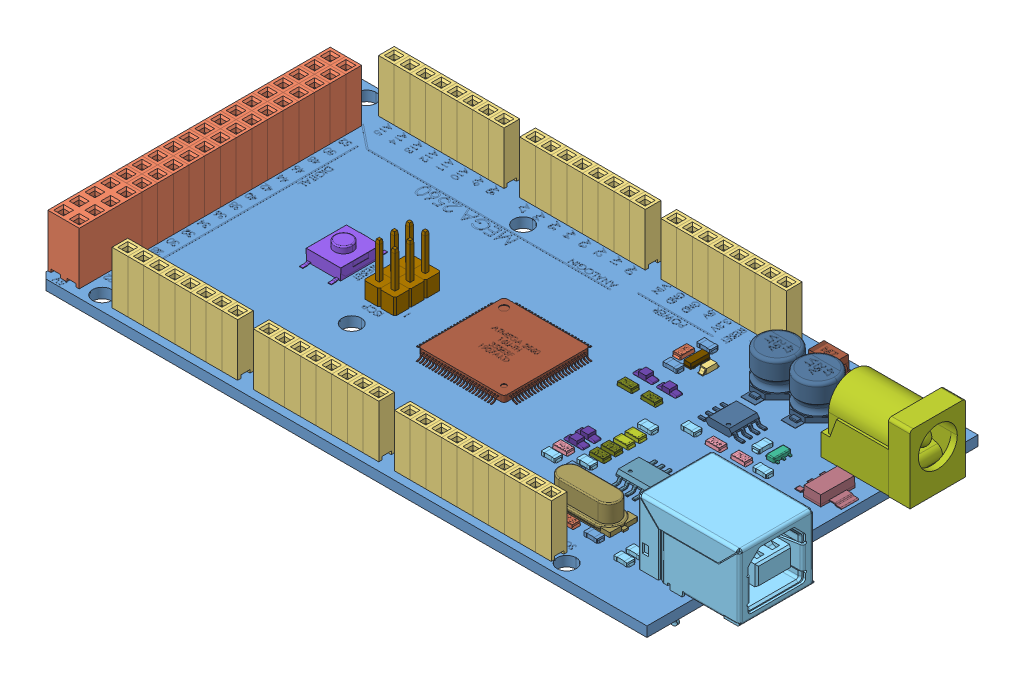
SolidWorks assembly Arduino Mega ATmega 2560, configuration Default. Lengths in mm.
Overall size (109.91 15.26 53.6).
200 component instances, 29 part files, 0 mates.
Components (placement in the parent):
- Arduino Mega ATmega 2560.STEP-1: Arduino Mega ATmega 2560.STEP [Default] at origin size (109.91 15.26 53.6)
  - Arduino Mega PCB.STEP-1: Arduino Mega PCB.STEP [Default] at origin size (101.8 1.64 53.6)
  - headerFemalex18x2.STEP-1: headerFemalex18x2.STEP [Default] at (-44.415 1.63 17.88) x (0 0 -1) z (1 0 0) size (45.72 11.5 5.08)
  - headerFemale.STEP-1: headerFemale.STEP [Default] at (-30.205 1.63 24.23) size (2.54 11.5 2.54)
  - headerFemale.STEP-2: headerFemale.STEP [Default] at (-27.665 1.63 24.23) size (2.54 11.5 2.54)
  - headerFemale.STEP-3: headerFemale.STEP [Default] at (-25.125 1.63 24.23) size (2.54 11.5 2.54)
  - headerFemale.STEP-4: headerFemale.STEP [Default] at (-22.585 1.63 24.23) size (2.54 11.5 2.54)
  - headerFemale.STEP-5: headerFemale.STEP [Default] at (-20.045 1.63 24.23) size (2.54 11.5 2.54)
  - headerFemale.STEP-6: headerFemale.STEP [Default] at (-17.505 1.63 24.23) size (2.54 11.5 2.54)
  - headerFemale.STEP-7: headerFemale.STEP [Default] at (-14.965 1.63 24.23) size (2.54 11.5 2.54)
  - headerFemale.STEP-8: headerFemale.STEP [Default] at (-12.425 1.63 24.23) size (2.54 11.5 2.54)
  - headerFemale.STEP-9: headerFemale.STEP [Default] at (-7.345 1.63 24.23) size (2.54 11.5 2.54)
  - headerFemale.STEP-10: headerFemale.STEP [Default] at (-4.805 1.63 24.23) size (2.54 11.5 2.54)
  - headerFemale.STEP-11: headerFemale.STEP [Default] at (-2.265 1.63 24.23) size (2.54 11.5 2.54)
  - headerFemale.STEP-12: headerFemale.STEP [Default] at (0.275 1.63 24.23) size (2.54 11.5 2.54)
  - headerFemale.STEP-13: headerFemale.STEP [Default] at (2.815 1.63 24.23) size (2.54 11.5 2.54)
  - headerFemale.STEP-14: headerFemale.STEP [Default] at (5.355 1.63 24.23) size (2.54 11.5 2.54)
  - headerFemale.STEP-15: headerFemale.STEP [Default] at (7.895 1.63 24.23) size (2.54 11.5 2.54)
  - headerFemale.STEP-16: headerFemale.STEP [Default] at (10.435 1.63 24.23) size (2.54 11.5 2.54)
  - headerFemale.STEP-17: headerFemale.STEP [Default] at (15.515 1.63 24.23) size (2.54 11.5 2.54)
  - headerFemale.STEP-18: headerFemale.STEP [Default] at (18.055 1.63 24.23) size (2.54 11.5 2.54)
  - headerFemale.STEP-19: headerFemale.STEP [Default] at (20.595 1.63 24.23) size (2.54 11.5 2.54)
  - headerFemale.STEP-20: headerFemale.STEP [Default] at (23.135 1.63 24.23) size (2.54 11.5 2.54)
  - headerFemale.STEP-21: headerFemale.STEP [Default] at (25.675 1.63 24.23) size (2.54 11.5 2.54)
  - headerFemale.STEP-22: headerFemale.STEP [Default] at (28.215 1.63 24.23) size (2.54 11.5 2.54)
  - headerFemale.STEP-23: headerFemale.STEP [Default] at (30.755 1.63 24.23) size (2.54 11.5 2.54)
  - headerFemale.STEP-24: headerFemale.STEP [Default] at (33.295 1.63 24.23) size (2.54 11.5 2.54)
  - headerFemale.STEP-25: headerFemale.STEP [Default] at (35.835 1.63 24.23) size (2.54 11.5 2.54)
  - headerFemale.STEP-26: headerFemale.STEP [Default] at (38.375 1.63 24.23) size (2.54 11.5 2.54)
  - headerFemale.STEP-27: headerFemale.STEP [Default] at (-35.525 1.63 -24.23) size (2.54 11.5 2.54)
  - headerFemale.STEP-28: headerFemale.STEP [Default] at (-32.985 1.63 -24.23) size (2.54 11.5 2.54)
  - headerFemale.STEP-29: headerFemale.STEP [Default] at (-30.445 1.63 -24.23) size (2.54 11.5 2.54)
  - headerFemale.STEP-30: headerFemale.STEP [Default] at (-27.905 1.63 -24.23) size (2.54 11.5 2.54)
  - headerFemale.STEP-31: headerFemale.STEP [Default] at (-25.365 1.63 -24.23) size (2.54 11.5 2.54)
  - headerFemale.STEP-32: headerFemale.STEP [Default] at (-22.825 1.63 -24.23) size (2.54 11.5 2.54)
  - headerFemale.STEP-33: headerFemale.STEP [Default] at (-20.285 1.63 -24.23) size (2.54 11.5 2.54)
  - headerFemale.STEP-34: headerFemale.STEP [Default] at (-17.745 1.63 -24.23) size (2.54 11.5 2.54)
  - headerFemale.STEP-35: headerFemale.STEP [Default] at (-12.665 1.63 -24.23) size (2.54 11.5 2.54)
  - headerFemale.STEP-36: headerFemale.STEP [Default] at (-10.125 1.63 -24.23) size (2.54 11.5 2.54)
  - headerFemale.STEP-37: headerFemale.STEP [Default] at (-7.585 1.63 -24.23) size (2.54 11.5 2.54)
  - headerFemale.STEP-38: headerFemale.STEP [Default] at (-5.045 1.63 -24.23) size (2.54 11.5 2.54)
  - headerFemale.STEP-39: headerFemale.STEP [Default] at (-2.505 1.63 -24.23) size (2.54 11.5 2.54)
  - headerFemale.STEP-40: headerFemale.STEP [Default] at (0.035 1.63 -24.23) size (2.54 11.5 2.54)
  - headerFemale.STEP-41: headerFemale.STEP [Default] at (2.575 1.63 -24.23) size (2.54 11.5 2.54)
  - headerFemale.STEP-42: headerFemale.STEP [Default] at (5.115 1.63 -24.23) size (2.54 11.5 2.54)
  - headerFemale.STEP-43: headerFemale.STEP [Default] at (10.195 1.63 -24.23) size (2.54 11.5 2.54)
  - headerFemale.STEP-44: headerFemale.STEP [Default] at (12.735 1.63 -24.23) size (2.54 11.5 2.54)
  - headerFemale.STEP-45: headerFemale.STEP [Default] at (15.275 1.63 -24.23) size (2.54 11.5 2.54)
  - headerFemale.STEP-46: headerFemale.STEP [Default] at (17.815 1.63 -24.23) size (2.54 11.5 2.54)
  - headerFemale.STEP-47: headerFemale.STEP [Default] at (20.355 1.63 -24.23) size (2.54 11.5 2.54)
  - headerFemale.STEP-48: headerFemale.STEP [Default] at (22.895 1.63 -24.23) size (2.54 11.5 2.54)
  - headerFemale.STEP-49: headerFemale.STEP [Default] at (25.435 1.63 -24.23) size (2.54 11.5 2.54)
  - headerFemale.STEP-50: headerFemale.STEP [Default] at (27.975 1.63 -24.23) size (2.54 11.5 2.54)
  - solder.STEP-1: solder.STEP [Default] at (-46.9277 0 24.2186) x (-0.837169 0 -0.546944) z (-0.546944 0 0.837169) size (1.17 0.65 1.17)
  - solder.STEP-2: solder.STEP [Default] at (-44.3877 0 24.2186) x (-0.837169 0 -0.546944) z (-0.546944 0 0.837169) size (1.17 0.65 1.17)
  - solder.STEP-3: solder.STEP [Default] at (-46.9277 0 21.6786) x (-0.837169 0 -0.546944) z (-0.546944 0 0.837169) size (1.17 0.65 1.17)
  - solder.STEP-4: solder.STEP [Default] at (-44.3877 0 21.6786) x (-0.837169 0 -0.546944) z (-0.546944 0 0.837169) size (1.17 0.65 1.17)
  - solder.STEP-5: solder.STEP [Default] at (-46.9277 0 19.1386) x (-0.837169 0 -0.546944) z (-0.546944 0 0.837169) size (1.17 0.65 1.17)
  - solder.STEP-6: solder.STEP [Default] at (-44.3877 0 19.1386) x (-0.837169 0 -0.546944) z (-0.546944 0 0.837169) size (1.17 0.65 1.17)
  - solder.STEP-7: solder.STEP [Default] at (-46.9277 0 16.5986) x (-0.837169 0 -0.546944) z (-0.546944 0 0.837169) size (1.17 0.65 1.17)
  - solder.STEP-8: solder.STEP [Default] at (-44.3877 0 16.5986) x (-0.837169 0 -0.546944) z (-0.546944 0 0.837169) size (1.17 0.65 1.17)
  - solder.STEP-9: solder.STEP [Default] at (-46.9277 0 14.0586) x (-0.837169 0 -0.546944) z (-0.546944 0 0.837169) size (1.17 0.65 1.17)
  - solder.STEP-10: solder.STEP [Default] at (-44.3877 0 14.0586) x (-0.837169 0 -0.546944) z (-0.546944 0 0.837169) size (1.17 0.65 1.17)
  - solder.STEP-11: solder.STEP [Default] at (-46.9277 0 11.5186) x (-0.837169 0 -0.546944) z (-0.546944 0 0.837169) size (1.17 0.65 1.17)
  - solder.STEP-12: solder.STEP [Default] at (-44.3877 0 11.5186) x (-0.837169 0 -0.546944) z (-0.546944 0 0.837169) size (1.17 0.65 1.17)
  - solder.STEP-13: solder.STEP [Default] at (-46.9277 0 8.9786) x (-0.837169 0 -0.546944) z (-0.546944 0 0.837169) size (1.17 0.65 1.17)
  - solder.STEP-14: solder.STEP [Default] at (-44.3877 0 8.9786) x (-0.837169 0 -0.546944) z (-0.546944 0 0.837169) size (1.17 0.65 1.17)
  - solder.STEP-15: solder.STEP [Default] at (-46.9277 0 6.4386) x (-0.837169 0 -0.546944) z (-0.546944 0 0.837169) size (1.17 0.65 1.17)
  - solder.STEP-16: solder.STEP [Default] at (-44.3877 0 6.4386) x (-0.837169 0 -0.546944) z (-0.546944 0 0.837169) size (1.17 0.65 1.17)
  - solder.STEP-17: solder.STEP [Default] at (-46.9277 0 3.8986) x (-0.837169 0 -0.546944) z (-0.546944 0 0.837169) size (1.17 0.65 1.17)
  - solder.STEP-18: solder.STEP [Default] at (-44.3877 0 3.8986) x (-0.837169 0 -0.546944) z (-0.546944 0 0.837169) size (1.17 0.65 1.17)
  - solder.STEP-19: solder.STEP [Default] at (-46.9277 0 1.3586) x (-0.837169 0 -0.546944) z (-0.546944 0 0.837169) size (1.17 0.65 1.17)
  - solder.STEP-20: solder.STEP [Default] at (-44.3877 0 1.3586) x (-0.837169 0 -0.546944) z (-0.546944 0 0.837169) size (1.17 0.65 1.17)
  - solder.STEP-21: solder.STEP [Default] at (-46.9277 0 -1.1814) x (-0.837169 0 -0.546944) z (-0.546944 0 0.837169) size (1.17 0.65 1.17)
  - solder.STEP-22: solder.STEP [Default] at (-44.3877 0 -1.1814) x (-0.837169 0 -0.546944) z (-0.546944 0 0.837169) size (1.17 0.65 1.17)
  - solder.STEP-23: solder.STEP [Default] at (-46.9277 0 -3.7214) x (-0.837169 0 -0.546944) z (-0.546944 0 0.837169) size (1.17 0.65 1.17)
  - solder.STEP-24: solder.STEP [Default] at (-44.3877 0 -3.7214) x (-0.837169 0 -0.546944) z (-0.546944 0 0.837169) size (1.17 0.65 1.17)
  - solder.STEP-25: solder.STEP [Default] at (-46.9277 0 -6.2614) x (-0.837169 0 -0.546944) z (-0.546944 0 0.837169) size (1.17 0.65 1.17)
  - solder.STEP-26: solder.STEP [Default] at (-44.3877 0 -6.2614) x (-0.837169 0 -0.546944) z (-0.546944 0 0.837169) size (1.17 0.65 1.17)
  - solder.STEP-27: solder.STEP [Default] at (-46.9277 0 -8.8014) x (-0.837169 0 -0.546944) z (-0.546944 0 0.837169) size (1.17 0.65 1.17)
  - solder.STEP-28: solder.STEP [Default] at (-44.3877 0 -8.8014) x (-0.837169 0 -0.546944) z (-0.546944 0 0.837169) size (1.17 0.65 1.17)
  - solder.STEP-29: solder.STEP [Default] at (-46.9277 0 -11.3414) x (-0.837169 0 -0.546944) z (-0.546944 0 0.837169) size (1.17 0.65 1.17)
  - solder.STEP-30: solder.STEP [Default] at (-44.3877 0 -11.3414) x (-0.837169 0 -0.546944) z (-0.546944 0 0.837169) size (1.17 0.65 1.17)
  - solder.STEP-31: solder.STEP [Default] at (-46.9277 0 -13.8814) x (-0.837169 0 -0.546944) z (-0.546944 0 0.837169) size (1.17 0.65 1.17)
  - solder.STEP-32: solder.STEP [Default] at (-44.3877 0 -13.8814) x (-0.837169 0 -0.546944) z (-0.546944 0 0.837169) size (1.17 0.65 1.17)
  - solder.STEP-33: solder.STEP [Default] at (-46.9277 0 -16.4214) x (-0.837169 0 -0.546944) z (-0.546944 0 0.837169) size (1.17 0.65 1.17)
  - solder.STEP-34: solder.STEP [Default] at (-44.3877 0 -16.4214) x (-0.837169 0 -0.546944) z (-0.546944 0 0.837169) size (1.17 0.65 1.17)
  - solder.STEP-35: solder.STEP [Default] at (-46.9277 0 -18.9614) x (-0.837169 0 -0.546944) z (-0.546944 0 0.837169) size (1.17 0.65 1.17)
  - solder.STEP-36: solder.STEP [Default] at (-44.3877 0 -18.9614) x (-0.837169 0 -0.546944) z (-0.546944 0 0.837169) size (1.17 0.65 1.17)
  - solder.STEP-37: solder.STEP [Default] at (-36.5404 0 24.2186) x (-0.837169 0 -0.546944) z (-0.546944 0 0.837169) size (1.17 0.65 1.17)
  - solder.STEP-38: solder.STEP [Default] at (-34.0004 0 24.2186) x (-0.837169 0 -0.546944) z (-0.546944 0 0.837169) size (1.17 0.65 1.17)
  - solder.STEP-39: solder.STEP [Default] at (-31.4604 0 24.2186) x (-0.837169 0 -0.546944) z (-0.546944 0 0.837169) size (1.17 0.65 1.17)
  - solder.STEP-40: solder.STEP [Default] at (-28.9204 0 24.2186) x (-0.837169 0 -0.546944) z (-0.546944 0 0.837169) size (1.17 0.65 1.17)
  - solder.STEP-41: solder.STEP [Default] at (-26.3804 0 24.2186) x (-0.837169 0 -0.546944) z (-0.546944 0 0.837169) size (1.17 0.65 1.17)
  - solder.STEP-42: solder.STEP [Default] at (-23.8404 0 24.2186) x (-0.837169 0 -0.546944) z (-0.546944 0 0.837169) size (1.17 0.65 1.17)
  - solder.STEP-43: solder.STEP [Default] at (-21.3004 0 24.2186) x (-0.837169 0 -0.546944) z (-0.546944 0 0.837169) size (1.17 0.65 1.17)
  - solder.STEP-44: solder.STEP [Default] at (-18.7604 0 24.2186) x (-0.837169 0 -0.546944) z (-0.546944 0 0.837169) size (1.17 0.65 1.17)
  - solder.STEP-45: solder.STEP [Default] at (-13.6804 0 24.2186) x (-0.837169 0 -0.546944) z (-0.546944 0 0.837169) size (1.17 0.65 1.17)
  - solder.STEP-46: solder.STEP [Default] at (-11.1404 0 24.2186) x (-0.837169 0 -0.546944) z (-0.546944 0 0.837169) size (1.17 0.65 1.17)
  - solder.STEP-47: solder.STEP [Default] at (-8.6004 0 24.2186) x (-0.837169 0 -0.546944) z (-0.546944 0 0.837169) size (1.17 0.65 1.17)
  - solder.STEP-48: solder.STEP [Default] at (-6.0604 0 24.2186) x (-0.837169 0 -0.546944) z (-0.546944 0 0.837169) size (1.17 0.65 1.17)
  - solder.STEP-49: solder.STEP [Default] at (-3.5204 0 24.2186) x (-0.837169 0 -0.546944) z (-0.546944 0 0.837169) size (1.17 0.65 1.17)
  - solder.STEP-50: solder.STEP [Default] at (-0.9804 0 24.2186) x (-0.837169 0 -0.546944) z (-0.546944 0 0.837169) size (1.17 0.65 1.17)
  - solder.STEP-51: solder.STEP [Default] at (1.5596 0 24.2186) x (-0.837169 0 -0.546944) z (-0.546944 0 0.837169) size (1.17 0.65 1.17)
  - solder.STEP-52: solder.STEP [Default] at (4.0996 0 24.2186) x (-0.837169 0 -0.546944) z (-0.546944 0 0.837169) size (1.17 0.65 1.17)
  - solder.STEP-53: solder.STEP [Default] at (9.1796 0 24.2186) x (-0.837169 0 -0.546944) z (-0.546944 0 0.837169) size (1.17 0.65 1.17)
  - solder.STEP-54: solder.STEP [Default] at (11.7196 0 24.2186) x (-0.837169 0 -0.546944) z (-0.546944 0 0.837169) size (1.17 0.65 1.17)
  - solder.STEP-55: solder.STEP [Default] at (14.2596 0 24.2186) x (-0.837169 0 -0.546944) z (-0.546944 0 0.837169) size (1.17 0.65 1.17)
  - solder.STEP-56: solder.STEP [Default] at (16.7996 0 24.2186) x (-0.837169 0 -0.546944) z (-0.546944 0 0.837169) size (1.17 0.65 1.17)
  - solder.STEP-57: solder.STEP [Default] at (19.3396 0 24.2186) x (-0.837169 0 -0.546944) z (-0.546944 0 0.837169) size (1.17 0.65 1.17)
  - solder.STEP-58: solder.STEP [Default] at (21.8796 0 24.2186) x (-0.837169 0 -0.546944) z (-0.546944 0 0.837169) size (1.17 0.65 1.17)
  - solder.STEP-59: solder.STEP [Default] at (24.4196 0 24.2186) x (-0.837169 0 -0.546944) z (-0.546944 0 0.837169) size (1.17 0.65 1.17)
  - solder.STEP-60: solder.STEP [Default] at (26.9596 0 24.2186) x (-0.837169 0 -0.546944) z (-0.546944 0 0.837169) size (1.17 0.65 1.17)
  - solder.STEP-61: solder.STEP [Default] at (29.4996 0 24.2186) x (-0.837169 0 -0.546944) z (-0.546944 0 0.837169) size (1.17 0.65 1.17)
  - solder.STEP-62: solder.STEP [Default] at (32.0396 0 24.2186) x (-0.837169 0 -0.546944) z (-0.546944 0 0.837169) size (1.17 0.65 1.17)
  - solder.STEP-63: solder.STEP [Default] at (-41.8709 0 -24.251) x (-0.837169 0 -0.546944) z (-0.546944 0 0.837169) size (1.17 0.65 1.17)
  - solder.STEP-64: solder.STEP [Default] at (-39.3309 0 -24.251) x (-0.837169 0 -0.546944) z (-0.546944 0 0.837169) size (1.17 0.65 1.17)
  - solder.STEP-65: solder.STEP [Default] at (-36.7909 0 -24.251) x (-0.837169 0 -0.546944) z (-0.546944 0 0.837169) size (1.17 0.65 1.17)
  - solder.STEP-66: solder.STEP [Default] at (-34.2509 0 -24.251) x (-0.837169 0 -0.546944) z (-0.546944 0 0.837169) size (1.17 0.65 1.17)
  - solder.STEP-67: solder.STEP [Default] at (-31.7109 0 -24.251) x (-0.837169 0 -0.546944) z (-0.546944 0 0.837169) size (1.17 0.65 1.17)
  - solder.STEP-68: solder.STEP [Default] at (-29.1709 0 -24.251) x (-0.837169 0 -0.546944) z (-0.546944 0 0.837169) size (1.17 0.65 1.17)
  - solder.STEP-69: solder.STEP [Default] at (-26.6309 0 -24.251) x (-0.837169 0 -0.546944) z (-0.546944 0 0.837169) size (1.17 0.65 1.17)
  - solder.STEP-70: solder.STEP [Default] at (-24.0909 0 -24.251) x (-0.837169 0 -0.546944) z (-0.546944 0 0.837169) size (1.17 0.65 1.17)
  - solder.STEP-71: solder.STEP [Default] at (-19.0109 0 -24.251) x (-0.837169 0 -0.546944) z (-0.546944 0 0.837169) size (1.17 0.65 1.17)
  - solder.STEP-72: solder.STEP [Default] at (-16.4709 0 -24.251) x (-0.837169 0 -0.546944) z (-0.546944 0 0.837169) size (1.17 0.65 1.17)
  - solder.STEP-73: solder.STEP [Default] at (-13.9309 0 -24.251) x (-0.837169 0 -0.546944) z (-0.546944 0 0.837169) size (1.17 0.65 1.17)
  - solder.STEP-74: solder.STEP [Default] at (-11.3909 0 -24.251) x (-0.837169 0 -0.546944) z (-0.546944 0 0.837169) size (1.17 0.65 1.17)
  - solder.STEP-75: solder.STEP [Default] at (-8.8509 0 -24.251) x (-0.837169 0 -0.546944) z (-0.546944 0 0.837169) size (1.17 0.65 1.17)
  - solder.STEP-76: solder.STEP [Default] at (-6.3109 0 -24.251) x (-0.837169 0 -0.546944) z (-0.546944 0 0.837169) size (1.17 0.65 1.17)
  - solder.STEP-77: solder.STEP [Default] at (-3.7709 0 -24.251) x (-0.837169 0 -0.546944) z (-0.546944 0 0.837169) size (1.17 0.65 1.17)
  - solder.STEP-78: solder.STEP [Default] at (-1.2309 0 -24.251) x (-0.837169 0 -0.546944) z (-0.546944 0 0.837169) size (1.17 0.65 1.17)
  - solder.STEP-79: solder.STEP [Default] at (3.8491 0 -24.251) x (-0.837169 0 -0.546944) z (-0.546944 0 0.837169) size (1.17 0.65 1.17)
  - solder.STEP-80: solder.STEP [Default] at (6.3891 0 -24.251) x (-0.837169 0 -0.546944) z (-0.546944 0 0.837169) size (1.17 0.65 1.17)
  - solder.STEP-81: solder.STEP [Default] at (8.9291 0 -24.251) x (-0.837169 0 -0.546944) z (-0.546944 0 0.837169) size (1.17 0.65 1.17)
  - solder.STEP-82: solder.STEP [Default] at (11.4691 0 -24.251) x (-0.837169 0 -0.546944) z (-0.546944 0 0.837169) size (1.17 0.65 1.17)
  - solder.STEP-83: solder.STEP [Default] at (14.0091 0 -24.251) x (-0.837169 0 -0.546944) z (-0.546944 0 0.837169) size (1.17 0.65 1.17)
  - solder.STEP-84: solder.STEP [Default] at (16.5491 0 -24.251) x (-0.837169 0 -0.546944) z (-0.546944 0 0.837169) size (1.17 0.65 1.17)
  - solder.STEP-85: solder.STEP [Default] at (19.0891 0 -24.251) x (-0.837169 0 -0.546944) z (-0.546944 0 0.837169) size (1.17 0.65 1.17)
  - solder.STEP-86: solder.STEP [Default] at (21.6291 0 -24.251) x (-0.837169 0 -0.546944) z (-0.546944 0 0.837169) size (1.17 0.65 1.17)
  - USBInput.STEP-1: USBInput.STEP [Default] at (51.825 1.63 -24.14) x (0 0 1) z (-1 0 0) size (13.91 15.21 16.51)
  - solder.STEP-87: solder.STEP [Default] at (43.2353 0 12.6794) x (-0.837169 0 -0.546944) z (-0.546944 0 0.837169) size (1.17 0.65 1.17)
  - solder1.8.STEP-1: solder1.8.STEP [Default] at (47.8972 0 19.9763) x (-0.837169 0 -0.546944) z (-0.546944 0 0.837169) size (1.8 0.65 1.8)
  - solder1.8.STEP-2: solder1.8.STEP [Default] at (47.8972 0 7.7416) x (-0.837169 0 -0.546944) z (-0.546944 0 0.837169) size (1.8 0.65 1.8)
  - solder.STEP-88: solder.STEP [Default] at (43.2353 0 15.1294) x (-0.837169 0 -0.546944) z (-0.546944 0 0.837169) size (1.17 0.65 1.17)
  - solder.STEP-89: solder.STEP [Default] at (45.1853 0 12.6794) x (-0.837169 0 -0.546944) z (-0.546944 0 0.837169) size (1.17 0.65 1.17)
  - solder.STEP-90: solder.STEP [Default] at (45.1853 0 15.1294) x (-0.837169 0 -0.546944) z (-0.546944 0 0.837169) size (1.17 0.65 1.17)
  - PowerPlug.STEP-1: PowerPlug.STEP [Default] at (53.07 1.63 -23.075) x (0 0 1) z (-1 0 0) size (11.2 15.2 15.9)
  - smdPushButton.STEP-1: smdPushButton.STEP [Default] at (-25.845 1.63 0) x (0 0 -1) z (1 0 0) size (9.1 2.85 5.6)
  - headerMale.STEP-1: headerMale.STEP [Default] at (-17.525 1.63 2.54) size (2.54 11.1 2.54)
  - headerMale.STEP-2: headerMale.STEP [Default] at (-17.525 1.63 0.09) size (2.54 11.1 2.54)
  - headerMale.STEP-3: headerMale.STEP [Default] at (-17.525 1.63 -2.36) size (2.54 11.1 2.54)
  - headerMale.STEP-4: headerMale.STEP [Default] at (-14.985 1.63 2.54) size (2.54 11.1 2.54)
  - headerMale.STEP-5: headerMale.STEP [Default] at (-14.985 1.63 0.09) size (2.54 11.1 2.54)
  - headerMale.STEP-6: headerMale.STEP [Default] at (-14.985 1.63 -2.36) size (2.54 11.1 2.54)
  - smd47.STEP-1: smd47.STEP [Default] at (33.2359 2.48 -17.65) x (0 0 1) z (-1 0 0) size (9.5 5.61 6.5)
  - smd47.STEP-2: smd47.STEP [Default] at (26.7359 2.48 -17.65) x (0 0 1) z (-1 0 0) size (9.5 5.61 6.5)
  - smdM7diode.STEP-1: smdM7diode.STEP [Default] at (28.3956 1.68 -24.2569) size (6.5 2.06 2.5)
  - smdCrystalOscillator.STEP-1: smdCrystalOscillator.STEP [Default] at (29.1027 1.83 15.1887) size (11.93 3.7 4.5)
  - VoltageRegulatorAMS1112.STEP-1: VoltageRegulatorAMS1112.STEP [Default] at (46.1008 1.63 -6.698) x (-0.008727 0 0.999962) z (-0.999962 0 -0.008727) size (5.5 1.65 6.7)
  - smdChip16pin.STEP-1: smdChip16pin.STEP [Default] at (36.9716 2.355 6.6448) x (0 0 1) z (-1 0 0) size (7.3 1.22 10)
  - tinyVoltageRegulator.STEP-1: tinyVoltageRegulator.STEP [Default] at (44.8587 1.63 1.7682) x (-0.008727 0 0.999962) z (-0.999962 0 -0.008727) size (2.75 0.7 2.1)
  - smdResistor102.STEP-1: smdResistor102.STEP [Default] at (15.0665 1.63 -5.1619) size (2.53 0.63 1.31)
  - smdResistor102.STEP-2: smdResistor102.STEP [Default] at (18.9101 1.63 -5.1619) size (2.53 0.63 1.31)
  - smdLED.STEP-1: smdLED.STEP [Default] at (15.1024 1.68 -8.0155) size (3.23 0.89 1.26)
  - smdLED.STEP-2: smdLED.STEP [Default] at (18.924 1.68 -8.0155) size (3.23 0.89 1.26)
  - tinyCrystal.STEP-1: tinyCrystal.STEP [Default] at (17.0851 1.63 -14.2329) x (-0.008727 0 0.999962) z (-0.999962 0 -0.008727) size (3.1 0.8 1.45)
  - smdceramiccapacitorwhite.STEP-1: smdceramiccapacitorwhite.STEP [Default] at (15.9897 1.63 -17.0687) size (2.52 0.61 1.3)
  - smdceramiccapacitorwhite.STEP-2: smdceramiccapacitorwhite.STEP [Default] at (15.9897 1.63 -11.5964) size (2.52 0.61 1.3)
  - smdResistor105.STEP-1: smdResistor105.STEP [Default] at (14.9012 1.63 -14.3439) x (0.008727 0 -0.999962) z (0.999962 0 0.008727) size (2.53 0.63 1.31)
  - tinyDiode.STEP-1: tinyDiode.STEP [Default] at (19.1387 1.64 -14.1257) x (0.008727 0 -0.999962) z (0.999962 0 0.008727) size (2.77 0.81 1)
  - smdResistor103.STEP-1: smdResistor103.STEP [Default] at (30.4879 1.63 -4.0203) size (2.53 0.63 1.31)
  - smdResistor103.STEP-2: smdResistor103.STEP [Default] at (34.5333 1.63 -4.0924) size (2.53 0.63 1.31)
  - smdceramiccapacitor.STEP-1: smdceramiccapacitor.STEP [Default] at (38.0044 1.63 -4.0975) size (2.52 0.61 1.3)
  - smdceramiccapacitor.STEP-2: smdceramiccapacitor.STEP [Default] at (34.4647 1.63 -7.4993) x (0.008727 0 -0.999962) z (0.999962 0 0.008727) size (2.52 0.61 1.3)
  - smdceramiccapacitor.STEP-3: smdceramiccapacitor.STEP [Default] at (26.4038 1.7166 -4.0641) size (2.52 0.61 1.3)
  - tinyVoltageRegulator5pins.STEP-1: tinyVoltageRegulator5pins.STEP [Default] at (36.9485 1.63 -7.6363) x (-0.008727 0 0.999962) z (-0.999962 0 -0.008727) size (2.75 0.7 2.1)
  - smdceramiccapacitorwhite.STEP-3: smdceramiccapacitorwhite.STEP [Default] at (22.5361 1.63 10.8878) size (2.52 0.61 1.3)
  - smdceramiccapacitor.STEP-4: smdceramiccapacitor.STEP [Default] at (22.5508 1.63 8.9496) size (2.52 0.61 1.3)
  - smdResistor102.STEP-3: smdResistor102.STEP [Default] at (22.6192 1.63 6.9092) size (2.53 0.63 1.31)
  - smdResistor102.STEP-4: smdResistor102.STEP [Default] at (22.6192 1.63 5.022) size (2.53 0.63 1.31)
  - smdResistorNoNumber.STEP-1: smdResistorNoNumber.STEP [Default] at (22.6869 1.63 3.0647) size (2.53 0.62 1.31)
  - smdResistorNoNumber.STEP-2: smdResistorNoNumber.STEP [Default] at (22.6869 1.63 1.2353) size (2.53 0.62 1.31)
  - smdceramiccapacitor.STEP-5: smdceramiccapacitor.STEP [Default] at (22.5508 1.63 -0.8918) size (2.52 0.61 1.3)
  - smdceramiccapacitor.STEP-6: smdceramiccapacitor.STEP [Default] at (18.6684 1.63 10.7899) size (2.52 0.61 1.3)
  - smdResistor103.STEP-3: smdResistor103.STEP [Default] at (18.6293 1.63 8.8506) size (2.53 0.63 1.31)
  - smdLED.STEP-3: smdLED.STEP [Default] at (18.6733 1.68 6.7615) size (3.23 0.89 1.26)
  - smdLED.STEP-4: smdLED.STEP [Default] at (18.6733 1.68 4.9107) size (3.23 0.89 1.26)
  - smdceramiccapacitor.STEP-7: smdceramiccapacitor.STEP [Default] at (39.1596 1.63 19.5386) size (2.52 0.61 1.3)
  - smdceramiccapacitor.STEP-8: smdceramiccapacitor.STEP [Default] at (39.1596 1.63 17.5628) size (2.52 0.61 1.3)
  - smdceramiccapacitor.STEP-9: smdceramiccapacitor.STEP [Default] at (39.1596 1.63 7.9308) size (2.52 0.61 1.3)
  - smdResistorNoNumber.STEP-3: smdResistorNoNumber.STEP [Default] at (39.1794 1.63 11.6814) size (2.53 0.62 1.31)
  - smdResistorNoNumber.STEP-4: smdResistorNoNumber.STEP [Default] at (39.1794 1.63 13.8493) size (2.53 0.62 1.31)
  - 1.7mmSmdCeramicCapacitorgray.STEP-1: 1.7mmSmdCeramicCapacitorgray.STEP [Default] at (39.277 1.5726 15.6439) size (2.02 0.49 1.04)
  - 1.7mmSmdCeramicCapacitorgray.STEP-2: 1.7mmSmdCeramicCapacitorgray.STEP [Default] at (39.277 1.5726 9.803) size (2.02 0.49 1.04)
  - CrystalNo5.STEP-1: CrystalNo5.STEP [Default] at (48.5405 1.68 1.8508) x (0.008727 0 -0.999962) z (0.999962 0 0.008727) size (2.54 0.66 1.44)
  - smdceramiccapacitorwhite.STEP-4: smdceramiccapacitorwhite.STEP [Default] at (33.3846 1.63 18.6432) size (2.52 0.61 1.3)
  - smdceramiccapacitorwhite.STEP-5: smdceramiccapacitorwhite.STEP [Default] at (25.6965 1.63 18.6432) size (2.52 0.61 1.3)
  - smdResistor105.STEP-2: smdResistor105.STEP [Default] at (29.3693 1.63 18.6473) size (2.53 0.63 1.31)
  - smdChip8pin.STEP-1: smdChip8pin.STEP [Default] at (28.6276 2.355 -10.7802) size (7.3 1.22 4.5)
  - ATmega 2560.STEP-1: ATmega 2560.STEP [Default] at (0.3651 1.63 0.2251) size (16.31 1.01 16.31)
